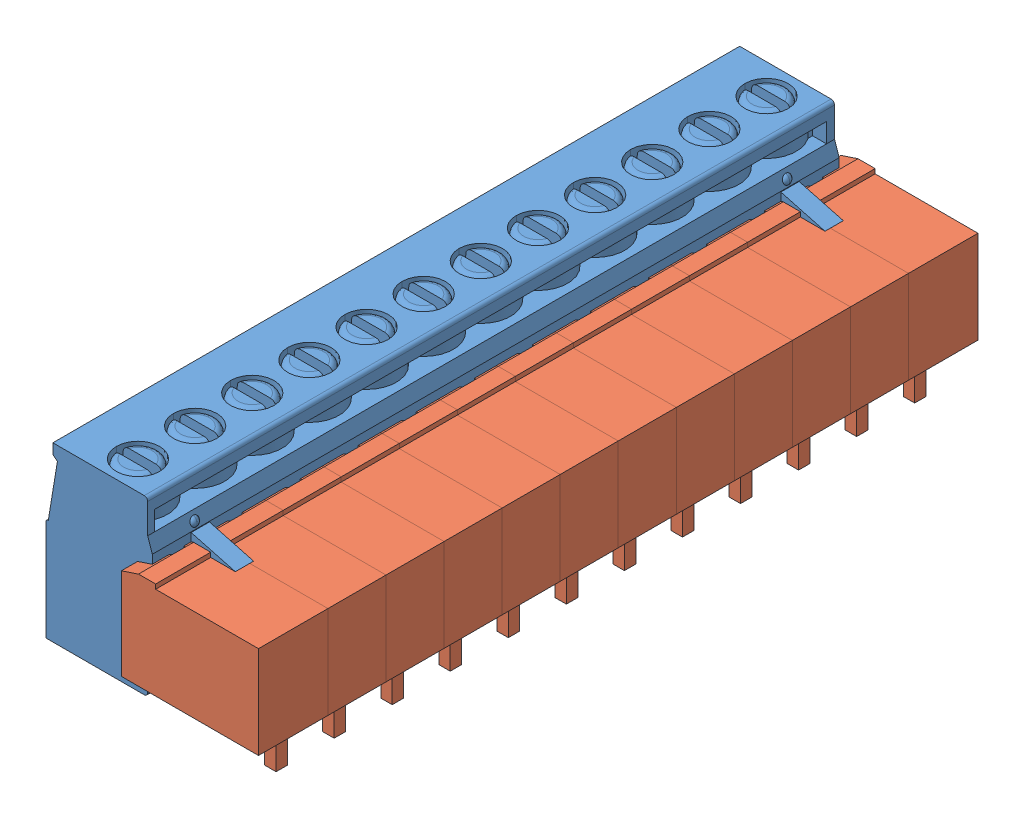
SolidWorks assembly Assem1, configuration Default. Lengths in mm.
Overall size (20.01 16.79 62.96).
2 component instances, 2 part files, 0 mates.
Components (placement in the parent):
- 20020007g121b01lf.stp-1: 20020007g121b01lf.stp [Default] at (-26.5725 51.4801 108.3551) x (0 0 -1) z (0 1 0) size (60.1 18.2 15.1)
- 20020110h121a01lf.stp-1: 20020110h121a01lf.stp [Default] at (-18.5614 42.0191 65.5135) x (0 0 1) z (-1 0 0) size (62.96 12 12)
